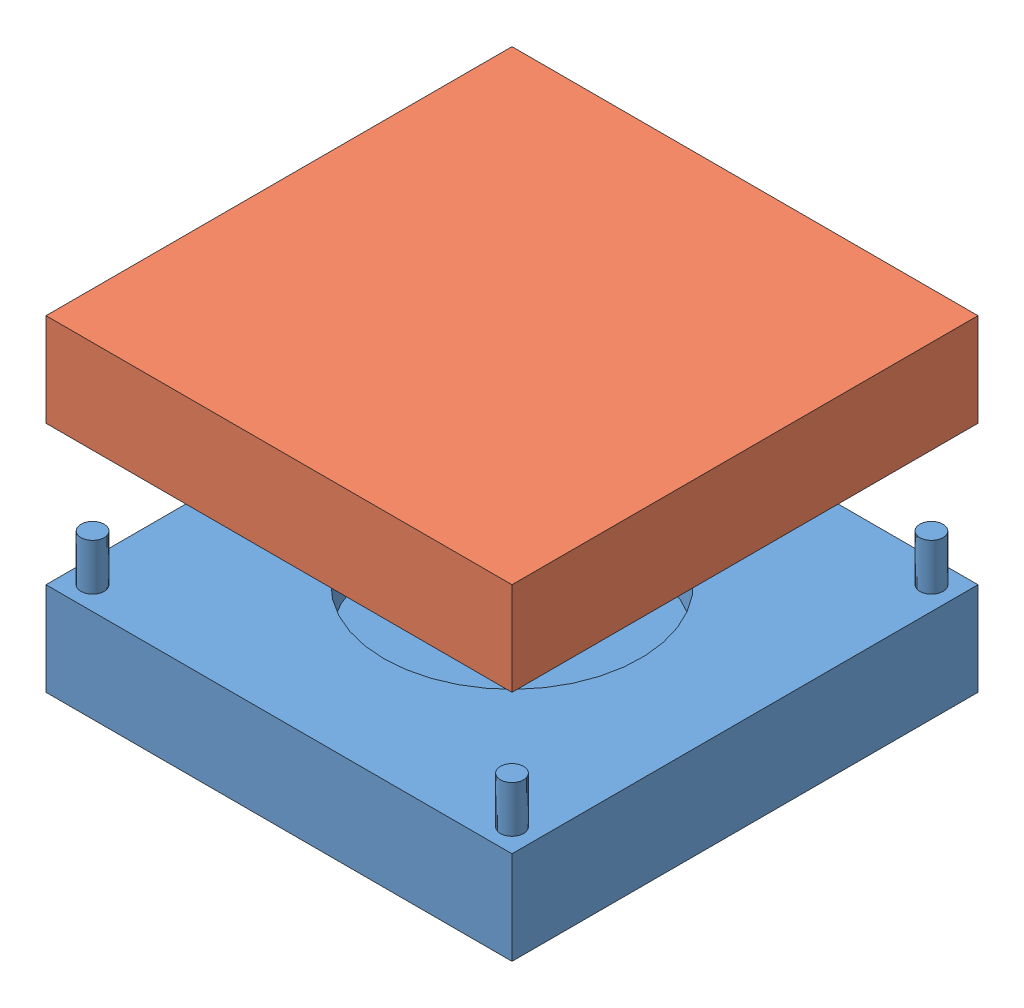
SolidWorks assembly Mold Assembly, configuration Default. Lengths in mm.
Overall size (100 70 100).
2 component instances, 2 part files, 3 mates.
Components (placement in the parent):
- BottomMold-1: BottomMold [Default] at (20.0314 63.7658 81.4148) size (100 30 100)
- Top Part-1: Top Part [Default] at (20.0314 93.7658 81.4148) size (100 30 100)
Mates (geometry in assembly coordinates):
- Concentric1: concentric aligned: cylinder of BottomMold-1 through (-24.9686 73.7658 126.4148) axis (0 -1 0) radius 2.5; cylinder of Top Part-1 through (-24.9686 103.7658 126.4148) axis (0 -1 0) radius 2.75
- Concentric2: concentric aligned: cylinder of BottomMold-1 through (65.0314 73.7658 126.4148) axis (0 -1 0) radius 2.5; cylinder of Top Part-1 through (65.0314 103.7658 126.4148) axis (0 -1 0) radius 2.75
- LimitDistance1: limit distance = 30 mm anti-aligned: plane of BottomMold-1 through (20.0314 63.7658 81.4148) normal (0 1 0); plane of Top Part-1 through (20.0314 93.7658 81.4148) normal (0 -1 0)
